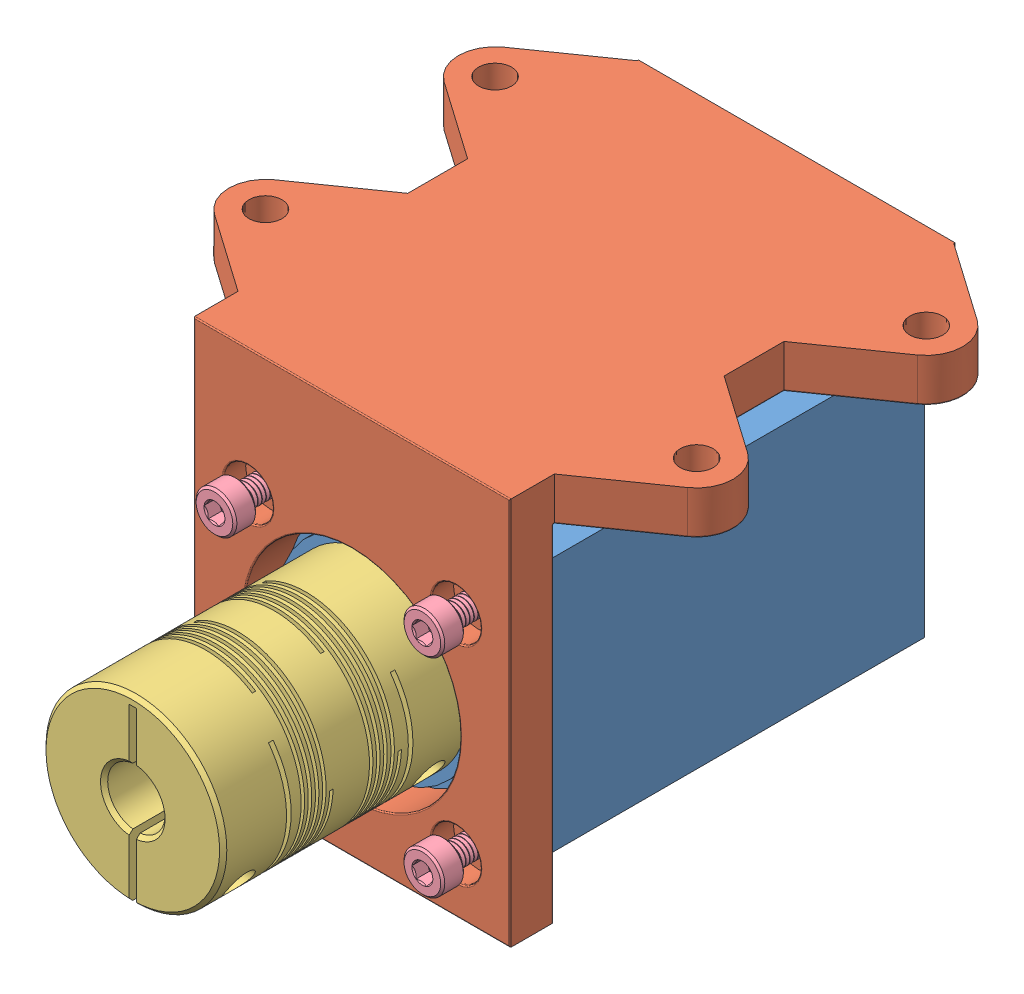
SolidWorks assembly nema11_assembly, configuration Default. Lengths in mm.
Overall size (55.8 42.94 73.5).
9 component instances, 4 part files, 8 mates.
Components (placement in the parent):
- nema11-1: nema11 [Default] at (-17.872 8.9792 -35.9393) size (28.2 28.2 64.5)
- nema11_mount-1: nema11_mount [motor_mount] at (13.728 5.5792 13.3232) x (-1 0 0) z (0 -1 0) size (55.8 49.21 42.94)
- shaft_coupling-1: shaft_coupling [2464K17] at (-3.772 23.0792 23.5607) x (0 -1 0) z (0 0 -1) size (21.03 20.92 28)
- 2.5mm_screw-1: 2.5mm_screw [91292A009] at (-15.272 11.5792 5.8232) x (-0.923728 -0.383049 0) z (0 0 -1) size (4.5 4.5 8.01)
- 2.5mm_screw-2: 2.5mm_screw [91292A009] at (-3.772 23.0792 9.5256) x (-0.923728 -0.383049 0) z (0 0 -1) size (4.5 4.5 8.01)
- 2.5mm_screw-3: 2.5mm_screw [91292A009] at (-15.272 34.5792 9.5256) x (-0.923728 -0.383049 0) z (0 0 -1) size (4.5 4.5 8.01)
- 2.5mm_screw-4: 2.5mm_screw [91292A009] at (7.728 34.5792 9.5256) x (-0.923728 -0.383049 0) z (0 0 -1) size (4.5 4.5 8.01)
- 2.5mm_screw-5: 2.5mm_screw [91292A009] at (7.728 11.5792 9.5256) x (-0.923728 -0.383049 0) z (0 0 -1) size (4.5 4.5 8.01)
- 2.5mm_screw-6: 2.5mm_screw [91292A009] at (-15.272 11.5792 9.5256) x (-0.923728 -0.383049 0) z (0 0 -1) size (4.5 4.5 8.01)
Mates (geometry in assembly coordinates):
- Concentric1: concentric: circle of assembly; circle of assembly; circle of nema11-1; circle of nema11_mount-1
- Coincident1: coincident: plane of assembly; plane of assembly; plane of nema11-1 through (-17.872 8.9792 8.5607) normal (0 0 1); plane of nema11_mount-1 through (13.728 5.5792 8.5607) normal (0 0 -1)
- Parallel1: parallel: plane of assembly; plane of assembly; plane of nema11-1 through (-17.872 8.9792 8.5607) normal (0 -1 0); plane of nema11_mount-1 through (13.728 43.7542 -35.8893) normal (0 -1 0)
- Distance1: distance = 1 mm: plane of assembly; plane of assembly; plane of shaft_coupling-1 through (-3.772 23.0792 9.5607) normal (0 0 -1); plane of nema11-1 through (-3.772 23.0792 10.5607) normal (0 0 1)
- Concentric2: concentric: circle of assembly; circle of assembly; circle of nema11-1; circle of shaft_coupling-1
- Parallel2: parallel: plane of assembly; plane of assembly; plane of nema11-1 through (-17.872 8.9792 8.5607) normal (-1 0 0); plane of shaft_coupling-1 through (-3.372 32.0792 16.5711) normal (-1 0 0)
- Coincident2: coincident: plane of assembly; plane of assembly; plane of nema11_mount-1 through (-16.622 11.5792 10.8232) normal (0 0 1); plane of 2.5mm_screw-1 through (-15.272 11.5792 10.8232) normal (0 0 -1)
- Concentric3: concentric: circle of assembly; circle of assembly; circle of nema11_mount-1; circle of 2.5mm_screw-1
